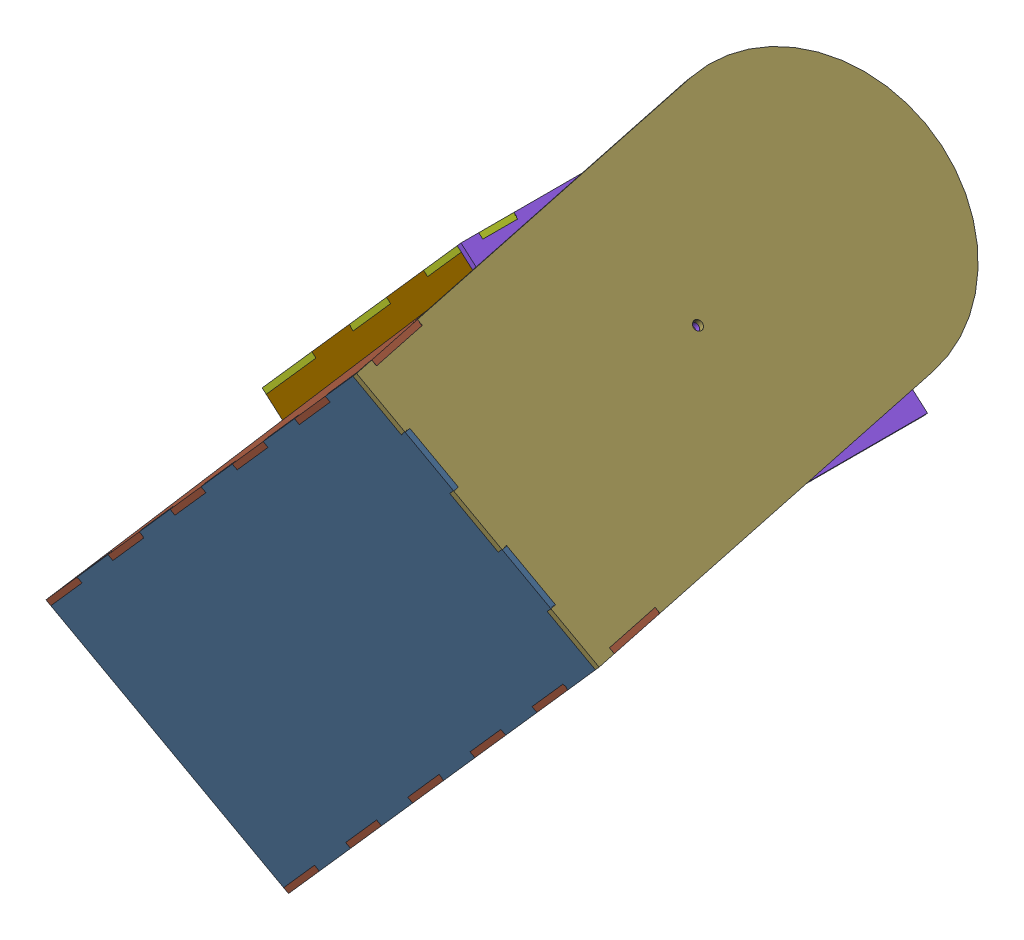
SolidWorks assembly 1u WoodSAT, configuration Default. Lengths in mm.
Overall size (317.51 310.65 323.04).
23 component instances, 13 part files, 3 mates.
Components (placement in the parent):
- 1u SAT-1: 1u SAT [Default] at (-472.4258 -187.0994 -7.3361) x (-0.286061 0.087401 -0.954217) z (0.879909 -0.370314 -0.297703) size (100 100 100)
  - SAT Side 1(10cm)-1: SAT Side 1(10cm) [Default] at (-20.815 1.3616 80.1149) size (100 100 3)
  - SAT Side 2(10cm)-1: SAT Side 2(10cm) [Default] at (-17.815 1.3616 -16.8851) x (0 0 1) z (-1 0 0) size (100 100 3)
  - SAT Top Bottom(10cm)-1: SAT Top Bottom(10cm) [Default] at (-20.815 1.3616 83.1149) size (100 3 100)
  - Part6^1u SAT-1: Part6^1u SAT [Default] at origin (virtual)
  - SAT Side 1(10cm)-2: SAT Side 1(10cm) [Default] at (-20.815 1.3616 -16.8851) size (100 100 3)
  - SAT Side 2(10cm)-2: SAT Side 2(10cm) [Default] at (79.185 1.3616 -16.8851) x (0 0 1) z (-1 0 0) size (100 100 3)
  - SAT Top Bottom(10cm)-2: SAT Top Bottom(10cm) [Default] at (-20.815 98.3616 83.1149) size (100 3 100)
- Axis 1-1: Axis 1 [Default] at (-497.06 7.151 -30.9384) x (-0.924982 0.379828 0.011744) z (-0.379379 -0.924786 0.029028) size (100 150 100)
  - SAT axis 1 wall-1: SAT axis 1 wall [Default] at (-169.6524 -82.3285 66.6178) size (100 150 3)
  - SAT axis 1 base-1: SAT axis 1 base [Default] at (-169.6524 -82.3285 166.6178) size (100 3 100)
  - SAT axis 1 support-1: SAT axis 1 support [Default] at (-72.6524 -82.3285 66.6178) size (3 40 100)
  - SAT axis 1 support-2: SAT axis 1 support [Default] at (-169.6524 -82.3285 66.6178) size (3 40 100)
- Axis 2-1: Axis 2 [Default] at (-554.3329 -212.057 130.8757) x (0.751014 -0.660285 -0.001651) z (0.659924 0.750682 -0.03127) size (150 150 160)
  - SAT axis 2 support-2: SAT axis 2 support [Default] at (-22.3526 70.2437 56.1156) x (-1 0 0) z (0 0 -1) size (3 39.25 160)
  - SAT axis 2 wall-1: SAT axis 2 wall [Default] at (-25.3526 70.2437 213.1156) x (1 0 0) z (0 -1 0) size (150 3 150)
  - SAT axis 2 base-2: SAT axis 2 base [Default] at (124.6474 70.2437 56.1156) x (-1 0 0) z (0 0 -1) size (150 3 160)
  - SAT axis 2 support-3: SAT axis 2 support [Default] at (124.6474 70.2437 56.1156) x (-1 0 0) z (0 0 -1) size (3 39.25 160)
- Axis 3-1: Axis 3 [Default] at (-240.5579 -59.8872 230.3813) x (-0.737816 0.655349 0.161695) z (-0.659924 -0.750682 0.03127) size (150 295 250)
  - SAT axis 3 base-1: SAT axis 3 base [Default] at (-31.5723 120.3552 349.0715) size (150 3 250)
  - SAT axis 3 support-1: SAT axis 3 support [Default] at (-31.5723 120.3552 349.0715) x (0 0 -1) z (1 0 0) size (250 49.4 3)
  - SAT axis 3 support-2: SAT axis 3 support [Default] at (115.4277 120.3552 349.0715) x (0 0 -1) z (1 0 0) size (250 49.4 3)
  - SAT axis 3 wall-1: SAT axis 3 wall [Default] at (-31.5723 120.3552 99.0715) size (150 295 3)
Mates (geometry in assembly coordinates):
- Coincident12: coincident anti-aligned: circle of Axis 2-1/SAT axis 2 wall-1; circle of Axis 3-1/SAT axis 3 wall-1
- Coincident16: coincident aligned: circle of Axis 1-1/SAT axis 1 base-1; circle of Axis 2-1/SAT axis 2 base-2
- Coincident17: coincident anti-aligned: circle of 1u SAT-1/SAT Top Bottom(10cm)-2; circle of Axis 1-1/SAT axis 1 wall-1
